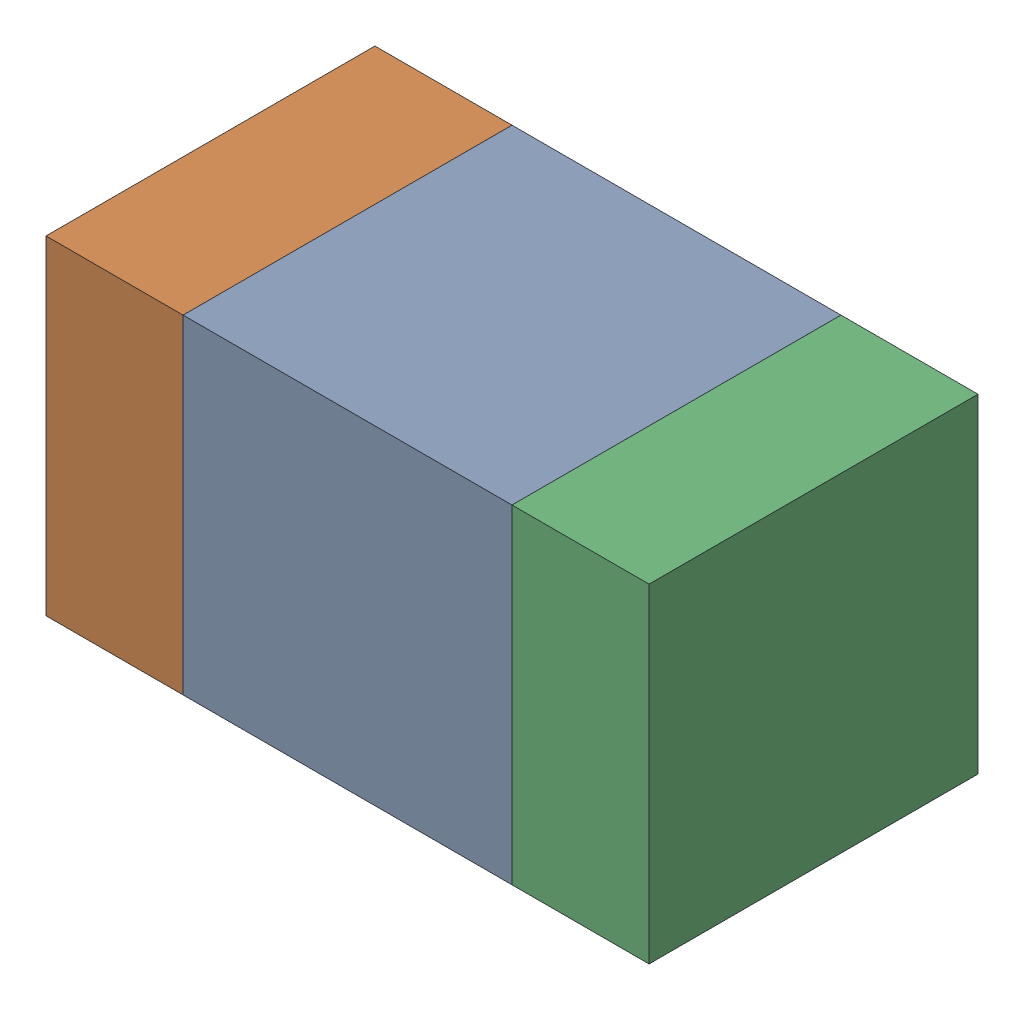
SolidWorks assembly C320_2PCB, configuration Default. Lengths in mm.
Overall size (1.1 0.6 0.6).
6 component instances, 2 part files, 0 mates.
Components (placement in the parent):
- 761606048-1: 761606048 [Default] at (132.9 86.7 -2.2638) size (0.6 0.6 0.6)
  - Extruded_9-1: Extruded_9 [Default] at origin size (0.6 0.6 0.6)
- 854785160-1: 854785160 [Default] at (132.475 86.7 -2.2638) size (0.25 0.6 0.6)
  - Extruded_19-1: Extruded_19 [Default] at origin size (0.25 0.6 0.6)
- 854785160-2: 854785160 [Default] at (133.325 86.7 -2.2638) size (0.25 0.6 0.6)
  - Extruded_19-1: Extruded_19 [Default] at origin size (0.25 0.6 0.6)
